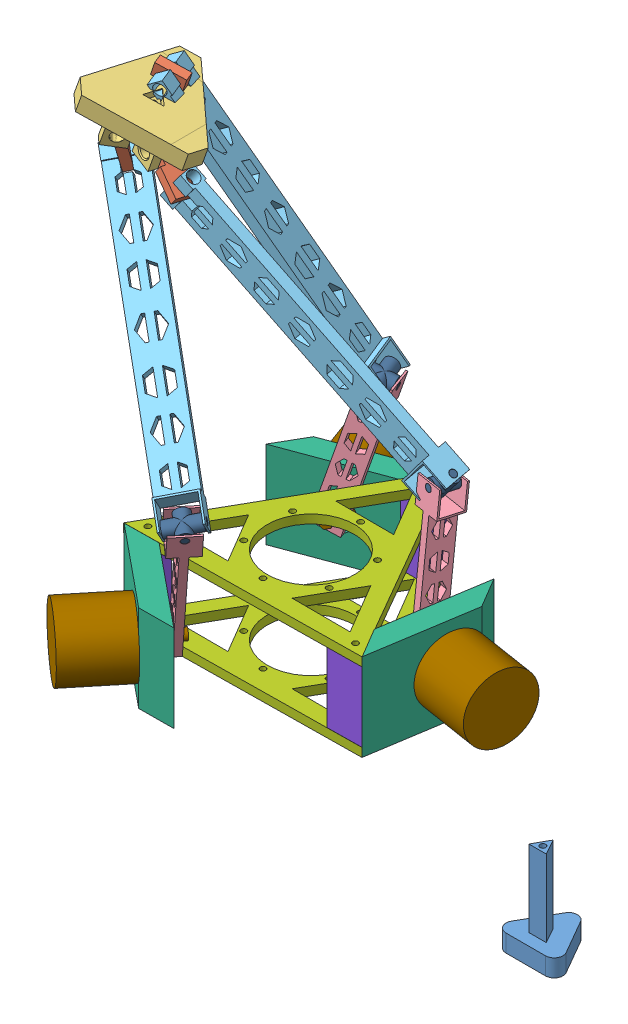
SolidWorks assembly 装配, configuration 默认. Lengths in mm.
Overall size (234.81 409.67 217.63).
25 component instances, 10 part files, 51 mates.
Components (placement in the parent):
- 顶板-控制-1: 顶板-控制 [默认] at (5.2503 11.0727 24.3186) size (32.68 54 29.64)
- 顶板-轴-1: 顶板-轴 [默认] at (-204.108 361.4671 99.5789) x (-0.006347 -0.955691 -0.294302) z (0.732241 -0.204874 0.6495) size (28.88 10 15)
- 顶部-板-1: 顶部-板 [默认] at (-184.715 372.0647 100.6915) x (-0.159602 0.101909 0.981907) z (0.937667 -0.295407 0.183071) size (81.49 62 55.82)
- 连杆-低-1: 连杆-低 [默认] at (-126.1608 158.3772 38.3103) x (0.896943 -0.291874 -0.332119) z (0.347239 0 0.937777) size (15 88 14.93)
- 连杆-高-1: 连杆-高 [默认] at (-203.8229 345.3261 95.0607) x (0.348212 0.748774 0.563991) z (0.644178 -0.628217 0.436323) size (15 20 168)
- 中心-固定板-1: 中心-固定板 [默认] at (-107.1241 142.1632 140.381) x (0.999979 0 -0.006459) z (0.006459 0 0.999979) size (66.18 50 38.31)
- 中心-固定环-1: 中心-固定环 [默认] at (-98.5237 142.224 92.6942) x (-0.494396 0 0.869237) z (-0.869237 0 -0.494396) size (156.46 5 156.46)
- 中心-支柱-1: 中心-支柱 [默认] at (-145.4382 147.224 132.8725) x (-0.505584 0 -0.862778) z (0.862778 0 -0.505584) size (20 40 17.32)
- 中心-支柱-2: 中心-支柱 [默认] at (-108.0179 147.224 31.8991) size (20 40 17.32)
- 中心-支柱-3: 中心-支柱 [默认] at (-40.7148 147.224 114.1244) x (-0.48877 0 0.872412) z (-0.872412 0 -0.48877) size (20 40 17.32)
- 中心-固定环-2: 中心-固定环 [默认] at (-98.5237 187.224 92.6942) x (-0.494396 0 0.869237) z (-0.869237 0 -0.494396) size (156.46 5 156.46)
- 编码器-1: 编码器 [默认] at (-23.4978 167.2711 86.8611) x (0.155422 0 -0.987848) z (0.987848 0 0.155422) size (38 38 55.5)
- 中心-固定板-2: 中心-固定板 [默认] at (-53.6076 142.2711 77.2716) x (-0.511146 0 -0.859494) z (0.859494 0 -0.511146) size (66.18 50 38.31)
- 中心-固定板-3: 中心-固定板 [默认] at (-133.8671 141.7686 61.1596) x (-0.5 0 0.866025) z (-0.866025 0 -0.5) size (66.18 50 38.31)
- 编码器-2: 编码器 [默认] at (-130.6207 167.1632 161.5108) x (-0.710184 -0.396838 -0.581514) z (-0.633535 0 0.773714) size (38 38 55.5)
- 编码器-3: 编码器 [默认] at (-140.2179 166.7686 30.2044) x (0.836724 0.451557 -0.309821) z (-0.347239 0 -0.937777) size (38 38 55.5)
- 连杆-低-2: 连杆-低 [默认] at (-109.7807 157.9998 151.3581) x (0.720481 -0.364514 0.589946) z (-0.633535 0 0.773714) size (15 88 14.93)
- 连杆-低-3: 连杆-低 [默认] at (-42.4637 161.0815 71.9168) x (0.154672 -0.098156 -0.983078) z (0.987848 0 0.155422) size (15 88 14.93)
- 万向节中心-1: 万向节中心 [默认] at (-44.2205 239.808 76.4091) x (0.7824 -0.595422 0.182548) z (0.603264 0.797395 0.015297) size (8 14.9 19.8)
- 万向节中心-2: 万向节中心 [默认] at (-115.2862 244.4193 29.4456) x (-0.316476 -0.948363 -0.021251) z (0.308766 -0.124168 0.942998) size (8 14.9 19.8)
- 万向节中心-3: 万向节中心 [默认] at (-91.4044 243.5726 160.7441) x (-0.130858 -0.90689 -0.400533) z (-0.681016 -0.211377 0.701097) size (8 14.9 19.8)
- 连杆-高-2: 连杆-高 [默认] at (-192.9974 380.3246 82.3298) x (0.816515 0.543093 -0.195841) z (0.487818 -0.830441 -0.269074) size (15 20 168)
- 连杆-高-3: 连杆-高 [默认] at (-169.4134 345.1119 99.6527) x (-0.102566 0.096589 -0.990026) z (0.790919 -0.595678 -0.140054) size (15 20 168)
- 顶板-轴-2: 顶板-轴 [默认] at (-192.3953 356.6151 79.0638) x (0.330572 0.943645 0.016014) z (-0.891844 0.306784 0.332412) size (28.88 10 15)
- 顶板-轴-3: 顶板-轴 [默认] at (-181.1462 354.0393 100.259) x (0.781409 -0.594791 0.188744) z (0.159602 -0.101909 -0.981907) size (28.88 10 15)
Mates (geometry in assembly coordinates):
- 同心1: concentric anti-aligned: circle of 中心-固定环-1; circle of 中心-支柱-2
- 平行5: parallel anti-aligned: line of 中心-固定环-1 through (-30.5236 147.224 131.3706) axis (-0.5 0 -0.866025); line of 中心-支柱-2 through (-98.0179 147.224 14.5786) axis (0.5 0 0.866025)
- 重合11: coincident anti-aligned: plane of 中心-固定环-1 through (-98.5237 147.224 92.6942) normal (0 1 0); plane of 中心-支柱-3 through (-40.7148 147.224 114.1244) normal (0 -1 0)
- 同心3: concentric anti-aligned: circle of 中心-固定环-1; circle of 中心-支柱-3
- 平行6: parallel anti-aligned: line of 中心-固定环-1 through (-165.5019 147.224 133.1144) axis (0.999917 0 -0.012919); line of 中心-支柱-3 through (-30.4918 147.224 131.3143) axis (-0.999917 0 0.012919)
- 重合14: coincident anti-aligned: plane of 中心-固定环-1 through (-98.5237 147.224 92.6942) normal (0 1 0); plane of 中心-支柱-1 through (-145.4382 147.224 132.8725) normal (0 -1 0)
- 同心4: concentric aligned: circle of 中心-固定环-1; circle of 中心-支柱-1
- 平行9: parallel anti-aligned: plane of 中心-支柱-1 through (-145.4382 187.224 132.8725) normal (0 1 0); plane of 中心-固定环-2 through (-98.5237 187.224 92.6942) normal (0 -1 0)
- 重合22: coincident anti-aligned: line of 中心-固定环-1 through (-98.0184 147.224 14.4661) axis (-0.494396 0 0.869237); line of 中心-支柱-1 through (-165.4378 147.224 133.0017) axis (0.494396 0 -0.869237)
- 重合25: coincident: plane of 中心-固定板-1 through (-165.4378 192.1632 133.0017) normal (-0.006459 0 -0.999979); plane of 中心-支柱-1 through (-145.4382 187.224 132.8725) normal (0.006459 0 0.999979)
- 重合28: coincident: line of 中心-固定板-1 through (-165.4378 192.1632 133.0017) axis (0 -1 0); line of 中心-支柱-1 through (-165.4378 187.224 133.0017) axis (0 -1 0)
- 重合32: coincident: plane of 中心-支柱-3 through (-40.7148 187.224 114.1244) normal (0.859494 0 -0.511146); plane of 中心-固定板-2 through (-30.4918 192.2711 131.3143) normal (-0.859494 0 0.511146)
- 重合33: coincident aligned: line of 中心-支柱-3 through (-30.4918 187.224 131.3143) axis (0 -1 0); line of 中心-固定板-2 through (-30.4918 192.2711 131.3143) axis (0 -1 0)
- 重合34: coincident: plane of 中心-支柱-2 through (-108.0179 187.224 31.8991) normal (-0.866025 0 -0.5); plane of 中心-固定板-3 through (-98.0179 191.7686 14.5786) normal (0.866025 0 0.5)
- 重合35: coincident: line of 中心-支柱-2 through (-98.0179 187.224 14.5786) axis (0 -1 0); line of 中心-固定板-3 through (-98.0179 191.7686 14.5786) axis (0 -1 0)
- 同心5: concentric aligned: cylinder of 编码器-1 through (-28.4371 167.2711 86.084) axis (0.987848 0 0.155422) radius 10; cylinder of 中心-固定板-2 through (-72.8902 167.2711 79.09) axis (0.987848 0 0.155422) radius 10.1
- 重合36: coincident aligned: circle of 编码器-1; plane of 中心-固定板-2 through (-30.4918 192.2711 131.3143) normal (0.987848 0 0.155422)
- 同心6: concentric aligned: cylinder of 中心-固定板-3 through (-122.8559 166.7686 77.0932) axis (-0.347239 0 -0.937777) radius 10.1; cylinder of 编码器-3 through (-138.4817 166.7686 34.8933) axis (-0.347239 0 -0.937777) radius 10
- 重合37: coincident anti-aligned: plane of 中心-固定板-3 through (-98.0179 191.7686 14.5786) normal (-0.347239 0 -0.937777); plane of 编码器-3 through (-140.2179 166.7686 30.2044) normal (0.347239 0 0.937777)
- 重合38: coincident anti-aligned: plane of 中心-固定板-1 through (-165.4378 192.1632 133.0017) normal (-0.633535 0 0.773714); plane of 编码器-2 through (-130.6207 167.1632 161.5108) normal (0.633535 0 -0.773714)
- 同心7: concentric aligned: cylinder of 中心-固定板-1 through (-98.9439 167.1632 122.8251) axis (-0.633535 0 0.773714) radius 10.1; cylinder of 编码器-2 through (-127.453 167.1632 157.6422) axis (-0.633535 0 0.773714) radius 10
- 同心8: concentric aligned: cylinder of 连杆-低-1 through (-133.7001 166.7686 47.8068) axis (-0.347239 0 -0.937777) radius 3.3; cylinder of 编码器-3 through (-132.7522 166.7686 50.3666) axis (-0.347239 0 -0.937777) radius 3
- 距离2: distance = 2 mm anti-aligned: plane of 连杆-低-1 through (-119.919 245.4742 38.4386) normal (-0.347239 0 -0.937777); plane of 中心-固定板-3 through (-108.0179 191.7686 31.8991) normal (0.347239 0 0.937777)
- 同心9: concentric anti-aligned: cylinder of 编码器-2 through (-116.9997 167.1632 144.8759) axis (-0.633535 0 0.773714) radius 3; cylinder of 连杆-低-2 through (-121.2631 167.1632 150.0827) axis (0.633535 0 -0.773714) radius 3.3
- 距离3: distance = 2 mm anti-aligned: plane of 连杆-低-2 through (-104.1044 244.3929 164.1327) normal (-0.633535 0 0.773714); plane of 中心-固定板-1 through (-145.4382 192.1632 132.8725) normal (0.633535 0 -0.773714)
- 距离5: distance = 2 mm anti-aligned: plane of 连杆-低-3 through (-38.0283 247.621 84.1815) normal (0.987848 0 0.155422); plane of 中心-固定板-2 through (-40.7148 192.2711 114.1244) normal (-0.987848 0 -0.155422)
- 同心10: concentric anti-aligned: cylinder of 编码器-1 through (-44.7366 167.2711 83.5196) axis (0.987848 0 0.155422) radius 3; circle of 连杆-低-3
- 同心11: concentric aligned: cylinder of 连杆-低-3 through (-33.9716 243.8079 45.5292) axis (-0.154672 0.098156 0.983078) radius 2; cylinder of 万向节中心-1 through (-37.6992 246.1735 69.2213) axis (-0.154672 0.098156 0.983078) radius 1.9
- 距离6: distance = 0.1 mm anti-aligned: plane of 万向节中心-1 through (-37.8538 246.2717 70.2044) normal (0.154672 -0.098156 -0.983078); plane of 连杆-低-3 through (-26.1522 235.2999 73.0392) normal (-0.154672 0.098156 0.983078)
- 同心12: concentric aligned: cylinder of 连杆-低-2 through (-74.7343 230.191 185.5966) axis (-0.720481 0.364514 -0.589946) radius 2; cylinder of 万向节中心-3 through (-92.0979 238.9757 171.3789) axis (-0.720481 0.364514 -0.589946) radius 1.9
- 重合44: coincident anti-aligned: plane of 连杆-低-2 through (-112.8216 233.7852 169.9195) normal (0.720481 -0.364514 0.589946); plane of 万向节中心-3 through (-102.1126 244.0425 163.1787) normal (-0.720481 0.364514 -0.589946)
- 重合45: coincident anti-aligned: plane of 连杆-低-1 through (-117.1716 234.6613 52.3502) normal (0.896943 -0.291874 -0.332119); plane of 万向节中心-2 through (-118.3235 245.1968 39.9805) normal (-0.896943 0.291874 0.332119)
- 同心13: concentric anti-aligned: cylinder of 连杆-低-1 through (-84.2397 234.1056 27.36) axis (-0.896943 0.291874 0.332119) radius 2; cylinder of 万向节中心-2 through (-119.2204 245.4887 40.3126) axis (0.896943 -0.291874 -0.332119) radius 1.9
- 重合46: coincident anti-aligned: plane of 万向节中心-2 through (-115.2862 244.4193 29.4456) normal (-0.308766 0.124168 -0.942998); plane of 连杆-高-2 through (-114.5284 257.6273 30.9366) normal (0.308766 -0.124168 0.942998)
- 同心14: concentric aligned: cylinder of 连杆-高-2 through (-121.4616 246.9027 10.5857) axis (0.308766 -0.124168 0.942998) radius 2; cylinder of 万向节中心-2 through (-115.595 244.5435 28.5026) axis (0.308766 -0.124168 0.942998) radius 1.9
- 重合47: coincident anti-aligned: plane of 连杆-高-1 through (-95.8788 256.0988 160.1745) normal (-0.681016 -0.211377 0.701097); plane of 万向节中心-3 through (-91.4044 243.5726 160.7441) normal (0.681016 0.211377 -0.701097)
- 同心17: concentric aligned: cylinder of 连杆-高-1 through (-77.7841 247.8002 146.7221) axis (-0.681016 -0.211377 0.701097) radius 2; cylinder of 万向节中心-3 through (-90.7234 243.784 160.043) axis (-0.681016 -0.211377 0.701097) radius 1.9
- 重合48: coincident anti-aligned: plane of 万向节中心-1 through (-33.4824 254.0016 76.6814) normal (0.603264 0.797395 0.015297); plane of 连杆-高-3 through (-42.9518 261.2785 70.7968) normal (-0.603264 -0.797395 -0.015297)
- 同心18: concentric anti-aligned: cylinder of 万向节中心-1 through (-32.8792 254.799 76.6967) axis (-0.603264 -0.797395 -0.015297) radius 1.9; cylinder of 连杆-高-3 through (-56.4065 223.7006 76.1001) axis (0.603264 0.797395 0.015297) radius 2
- 同心19: concentric anti-aligned: cylinder of 顶板-轴-1 through (-196.7856 359.4184 106.0739) axis (0.732241 -0.204874 0.6495) radius 3.3; cylinder of 顶部-板-1 through (-207.7692 362.4915 96.3314) axis (-0.732241 0.204874 -0.6495) radius 3.3
- 重合51: coincident: point of 顶板-轴-1; plane of 顶部-板-1 through (-200.8442 353.779 93.4742) normal (0.732241 -0.204874 0.6495)
- 同心20: concentric aligned: cylinder of 顶部-板-1 through (-205.7729 361.2168 84.05) axis (-0.891844 0.306784 0.332412) radius 3.3; cylinder of 顶板-轴-2 through (-201.3137 359.6829 82.3879) axis (-0.891844 0.306784 0.332412) radius 3.3
- 重合54: coincident anti-aligned: plane of 顶部-板-1 through (-186.9768 349.6082 100.068) normal (-0.891844 0.306784 0.332412); plane of 顶板-轴-2 through (-192.3953 356.6151 79.0638) normal (0.891844 -0.306784 -0.332412)
- 同心21: concentric anti-aligned: cylinder of 顶部-板-1 through (-181.9442 354.5489 105.1686) axis (-0.159602 0.101909 0.981907) radius 3.3; cylinder of 顶板-轴-3 through (-179.5502 353.0202 90.44) axis (0.159602 -0.101909 -0.981907) radius 3.3
- 重合55: coincident anti-aligned: plane of 顶部-板-1 through (-189.4589 349.8588 89.1575) normal (-0.159602 0.101909 0.981907); plane of 顶板-轴-3 through (-179.5502 353.0202 90.44) normal (0.159602 -0.101909 -0.981907)
- 重合56: coincident anti-aligned: plane of 顶板-轴-1 through (-193.404 336.6104 98.9162) normal (0.681016 0.211377 -0.701097); plane of 连杆-高-1 through (-207.5955 334.0185 84.3498) normal (-0.681016 -0.211377 0.701097)
- 同心23: concentric anti-aligned: cylinder of 顶板-轴-1 through (-202.2705 341.6671 98.96) axis (-0.681016 -0.211377 0.701097) radius 3.3; cylinder of 连杆-高-1 through (-207.4122 340.0712 104.2533) axis (0.681016 0.211377 -0.701097) radius 3.3
- 重合57: coincident anti-aligned: plane of 连杆-高-2 through (-205.1284 371.4155 87.8329) normal (-0.308766 0.124168 -0.942998); plane of 顶板-轴-2 through (-188.6871 364.6866 81.5635) normal (0.308766 -0.124168 0.942998)
- 同心24: concentric anti-aligned: cylinder of 连杆-高-2 through (-187.4706 374.9307 90.4144) axis (-0.308766 0.124168 -0.942998) radius 3.3; cylinder of 顶板-轴-2 through (-189.7709 375.8557 83.3891) axis (0.308766 -0.124168 0.942998) radius 3.3
- 重合64: coincident anti-aligned: plane of 连杆-高-3 through (-166.2523 345.6171 115.3553) normal (-0.603264 -0.797395 -0.015297); plane of 顶板-轴-3 through (-172.6972 350.7496 101.9738) normal (0.603264 0.797395 0.015297)
- 同心25: concentric anti-aligned: cylinder of 连杆-高-3 through (-159.4262 350.1074 99.1054) axis (-0.603264 -0.797395 -0.015297) radius 3.3; cylinder of 顶板-轴-3 through (-163.9205 344.1668 98.9915) axis (0.603264 0.797395 0.015297) radius 3.3
